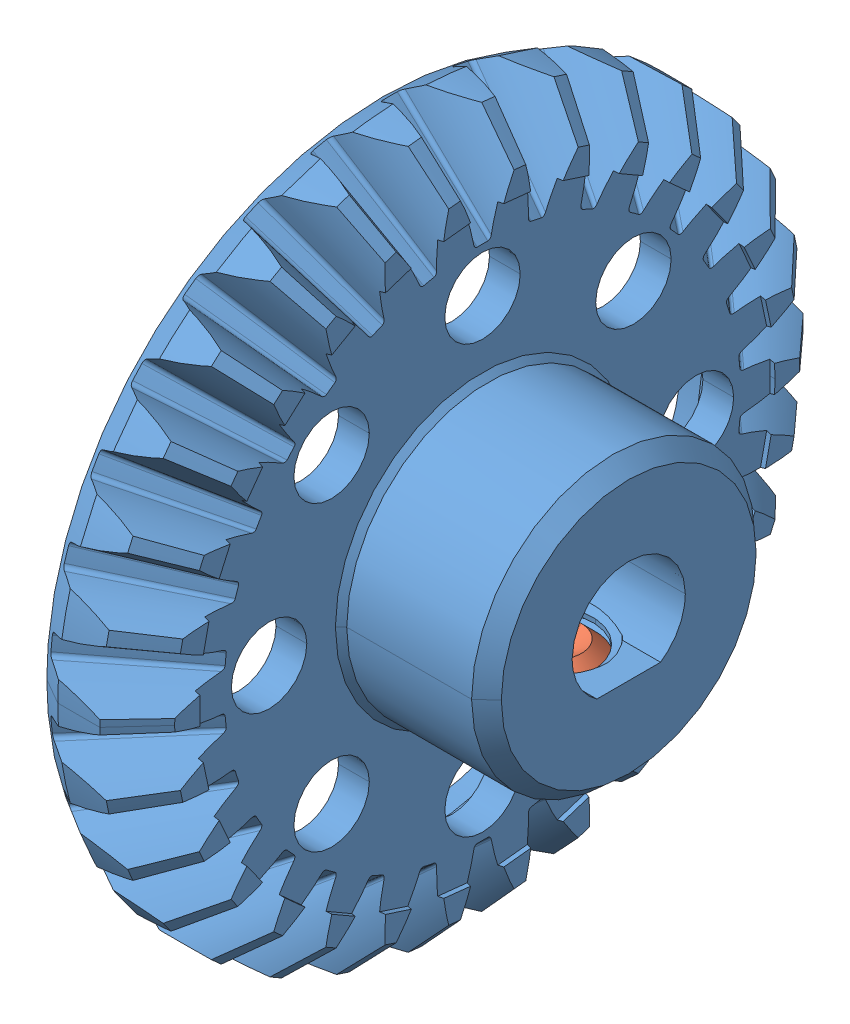
SolidWorks assembly 30 tooth bevel gear D shaft, configuration Default. Lengths in mm.
Overall size (13 40.49 40.63).
2 component instances, 2 part files, 0 mates.
Components (placement in the parent):
- 2315-1006-0030.STEP-1: 2315-1006-0030.STEP [Default] at (-63.2694 29.6641 7.955) size (13 40.49 40.63)
- 2806-0005-0004_91390A117.STEP-1: 2806-0005-0004_91390A117.STEP [Default] at (-50.6406 24.7725 7.955) x (1 0 0) z (0 -1 0) size (5.01 5.01 4.01)
